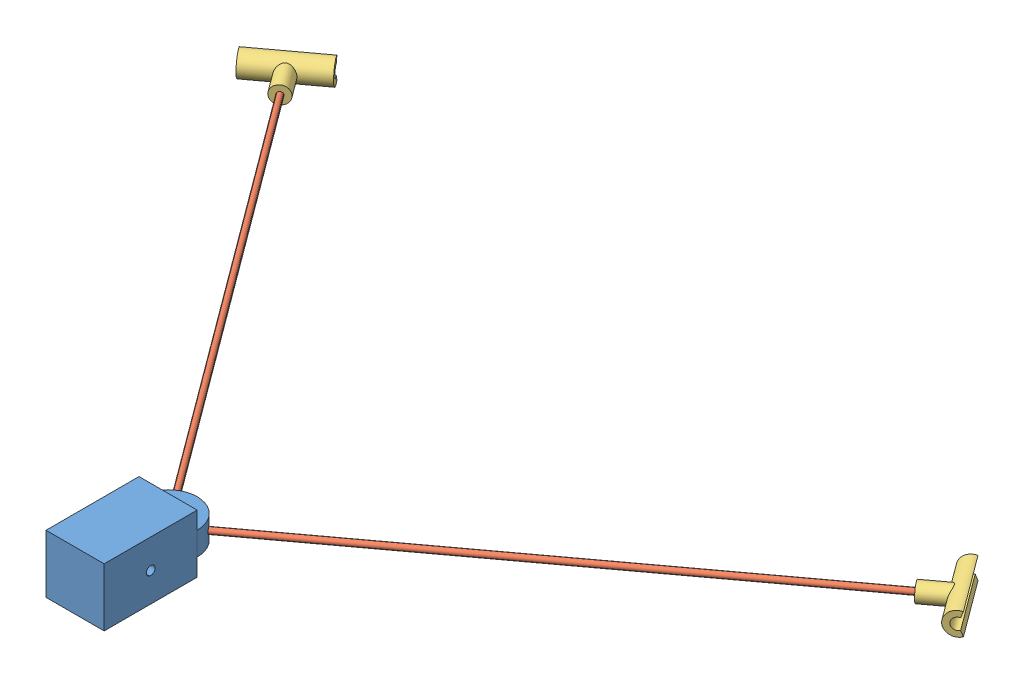
SolidWorks assembly wirePropMount, configuration Default. Lengths in mm.
Overall size (232.44 15.88 157).
5 component instances, 3 part files, 10 mates.
Components (placement in the parent):
- rodMount1-1: rodMount1 [Default] at (13.6383 18.9019 15.2057) size (15.88 15.88 33.34)
- rod-1: rod [Default] at (13.6383 18.9019 15.2057) x (0.656472 0.577129 -0.485764) z (-0.594823 0 -0.803857) size (3.17 3.17 152.4)
- rod-2: rod [Default] at (136.1461 18.9019 -75.4453) x (-0.310525 -0.852917 -0.41965) z (-0.803857 0 0.594823) size (3.17 3.17 152.4)
- gaurdBracket-1: gaurdBracket [Default] at (-78.9012 18.9019 -109.8543) x (0.803857 0 -0.594823) z (0.594823 0 0.803857) size (19.05 6.35 10.61)
- gaurdBracket-2: gaurdBracket [Default] at (138.6984 18.9019 -77.3339) x (0.594823 0 0.803857) z (-0.803857 0 0.594823) size (19.05 6.35 10.61)
Mates (geometry in assembly coordinates):
- Concentric1: concentric aligned: cylinder of rodMount1-1 through (13.6383 18.9019 15.2057) axis (0.803857 0 -0.594823) radius 1.5875; cylinder of rod-2 through (13.6383 18.9019 15.2057) axis (0.803857 0 -0.594823) radius 1.5875
- Coincident1: coincident anti-aligned: plane of rodMount1-1 through (13.6383 18.9019 15.2057) normal (0.803857 0 -0.594823); plane of rod-2 through (13.6383 18.9019 15.2057) normal (-0.803857 0 0.594823)
- Coincident2: coincident anti-aligned: plane of rodMount1-1 through (13.6383 18.9019 15.2057) normal (-0.594823 0 -0.803857); plane of rod-1 through (13.6383 18.9019 15.2057) normal (0.594823 0 0.803857)
- Concentric2: concentric anti-aligned: cylinder of rodMount1-1 through (13.6383 18.9019 15.2057) axis (-0.594823 0 -0.803857) radius 1.5875; cylinder of rod-1 through (-77.0127 18.9019 -107.3021) axis (0.594823 0 0.803857) radius 1.5875
- Coincident3: coincident aligned: cylinder of rod-1 through (-77.0127 18.9019 -107.3021) axis (0.594823 0 0.803857) radius 1.5875; circle of gaurdBracket-1
- Tangent1: tangent anti-aligned: plane of rod-1 through (-77.0127 18.9019 -107.3021) normal (-0.594823 0 -0.803857); cylinder of gaurdBracket-1 through (-71.2445 18.9019 -115.52) axis (-0.803857 0 0.594823) radius 3.175
- Parallel1: parallel: line of gaurdBracket-1 through (-78.9012 18.9019 -109.8543) axis (-0.803857 0 0.594823); plane of assembly
- Concentric3: concentric aligned: cylinder of rod-2 through (13.6383 18.9019 15.2057) axis (0.803857 0 -0.594823) radius 1.5875; cylinder of gaurdBracket-2 through (131.0416 18.9019 -71.6682) axis (0.803857 0 -0.594823) radius 1.5875
- Tangent2: tangent anti-aligned: plane of rod-2 through (136.1461 18.9019 -75.4453) normal (0.803857 0 -0.594823); cylinder of gaurdBracket-2 through (144.3641 18.9019 -69.6771) axis (-0.594823 0 -0.803857) radius 3.175
- Parallel2: parallel: line of gaurdBracket-2 through (138.6984 18.9019 -77.3339) axis (-0.594823 0 -0.803857); plane of assembly
